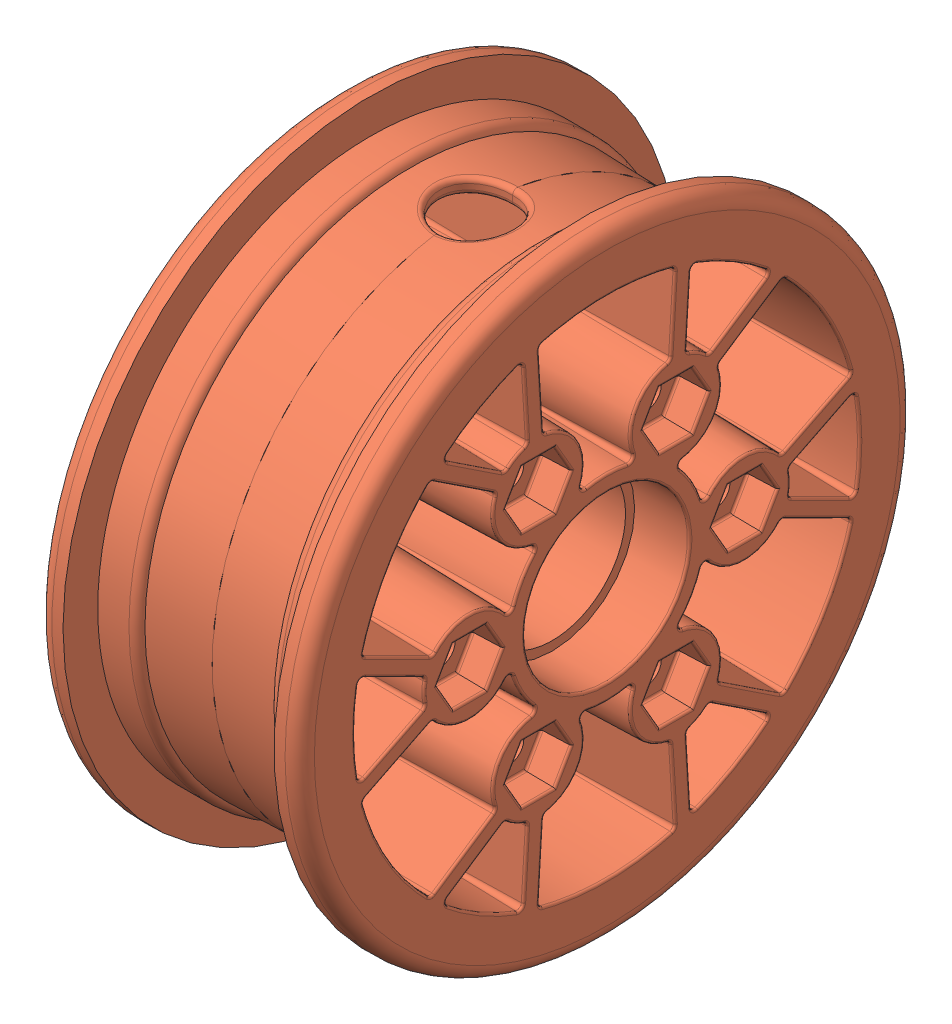
SolidWorks assembly Pneumatic Hub, configuration Default. Lengths in mm.
Overall size (45.47 106.55 106.55).
8 component instances, 2 part files, 0 mates.
Components (placement in the parent):
- #4x1.00, Plastic Thread Rolling Screw, Pan Head, Cross Recessed, Zinc Plated (Plastic Applications)_Fastenal__5E0B_15FCAA-1: #4x1.00, Plastic Thread Rolling Screw, Pan Head, Cross Recessed, Zinc Plated (Plastic Applications)_Fastenal__5E0B_15FCAA [Default] at (7.3269 34.0601 29.3991) x (-1 0 0) z (0 -0.924225 -0.381849) size (27.43 5.56 5.56)
- Hub-1: Hub [Default] at (-28.6141 -1.1351 9.0791) size (25.79 106.55 106.55)
- #4x1.00, Plastic Thread Rolling Screw, Pan Head, Cross Recessed, Zinc Plated (Plastic Applications)_Fastenal__5E0B_15FCAA-2: #4x1.00, Plastic Thread Rolling Screw, Pan Head, Cross Recessed, Zinc Plated (Plastic Applications)_Fastenal__5E0B_15FCAA [Default] at (7.3269 -1.1351 -31.5609) x (-1 0 0) z (0 0.131421 0.991327) size (27.43 5.56 5.56)
- #4x1.00, Plastic Thread Rolling Screw, Pan Head, Cross Recessed, Zinc Plated (Plastic Applications)_Fastenal__5E0B_15FCAA-3: #4x1.00, Plastic Thread Rolling Screw, Pan Head, Cross Recessed, Zinc Plated (Plastic Applications)_Fastenal__5E0B_15FCAA [Default] at (-19.0891 -1.1351 49.7191) x (1 0 0) z (0 -0.750107 0.661316) size (27.43 5.56 5.56)
- #4x1.00, Plastic Thread Rolling Screw, Pan Head, Cross Recessed, Zinc Plated (Plastic Applications)_Fastenal__5E0B_15FCAA-4: #4x1.00, Plastic Thread Rolling Screw, Pan Head, Cross Recessed, Zinc Plated (Plastic Applications)_Fastenal__5E0B_15FCAA [Default] at (7.3269 -36.3304 29.3991) x (-1 0 0) z (0 0.792804 -0.609477) size (27.43 5.56 5.56)
- #4x1.00, Plastic Thread Rolling Screw, Pan Head, Cross Recessed, Zinc Plated (Plastic Applications)_Fastenal__5E0B_15FCAA-5: #4x1.00, Plastic Thread Rolling Screw, Pan Head, Cross Recessed, Zinc Plated (Plastic Applications)_Fastenal__5E0B_15FCAA [Default] at (-19.0891 34.0601 -11.2409) x (1 0 0) z (0 0.94777 0.318954) size (27.43 5.56 5.56)
- #4x1.00, Plastic Thread Rolling Screw, Pan Head, Cross Recessed, Zinc Plated (Plastic Applications)_Fastenal__5E0B_15FCAA-6: #4x1.00, Plastic Thread Rolling Screw, Pan Head, Cross Recessed, Zinc Plated (Plastic Applications)_Fastenal__5E0B_15FCAA [Default] at (-19.0891 -36.3304 -11.2409) x (1 0 0) z (0 -0.197663 -0.98027) size (27.43 5.56 5.56)
- Hub-2: Hub [Default] at (16.8519 -1.1351 9.0791) x (-1 0 0) z (0 0 -1) size (25.79 106.55 106.55)
